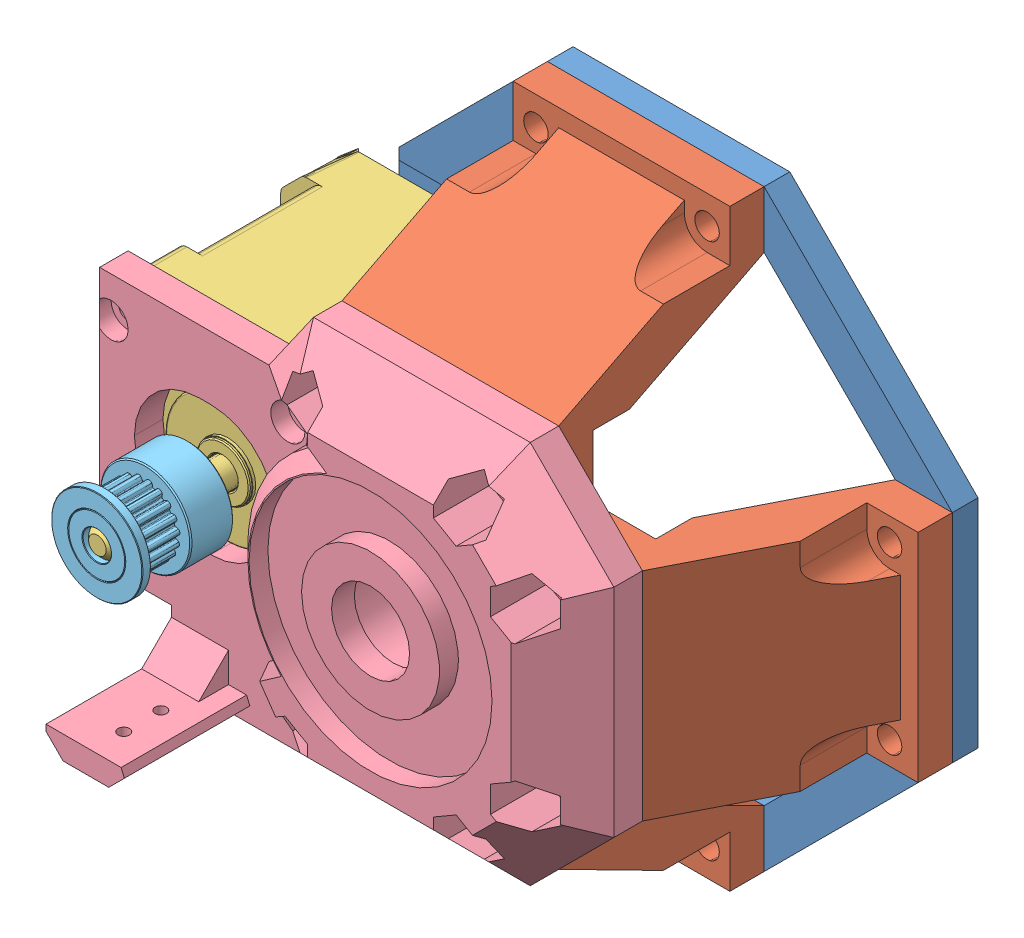
SolidWorks assembly 基座, configuration 默认. Lengths in mm.
7 component instances, 5 part files, 19 mates.
Components (placement in the parent):
- 基座底板-1: 基座底板 [默认] at origin size (101.5 104 4.5)
- 基座支架-1: 基座支架 [默认] at (148.9938 50.9835 0) x (0 -1 0) z (0 0 1) size (32 38 36)
- 基座支架-2: 基座支架 [默认] at origin size (32 38 36)
- 基座支架-3: 基座支架 [默认] at (50.9835 -148.9938 0) x (0 1 0) z (0 0 1) size (32 38 36)
- 基座电机-1: 基座电机 [默认] at (2.002 -0.002 0) size (51.25 48 66.15)
- 基座顶板-1: 基座顶板 [默认] at origin size (95.16 67.32 27)
- 基座小带轮-1: 基座小带轮 [默认] at (123.4059 0.6984 1.1039) x (-0.204066 -0.978957 0) z (0 0 1) size (16 16 16)
Mates (geometry in assembly coordinates):
- 重合1: coincident: plane of ? through (0 0 0) normal (0 0 1); plane of assembly through (0 0 0) normal (0 0 1)
- 重合2: coincident: plane of ? through (0 0 0) normal (0 1 0); plane of assembly through (0 0 0) normal (0 1 0)
- 重合3: coincident: plane of ? through (0 0 0) normal (1 0 0); plane of assembly through (0 0 0) normal (1 0 0)
- 重合4: coincident: plane of ? through (-96.0113 -266.0051 -63.2) normal (0 0 1); plane of 基座支架-1 through (80.9887 -93.5051 -63.2) normal (0 0 -1)
- 同心1: concentric: cylinder of ? through (84.9887 -96.0051 -63.2) axis (0 0 -1) radius 1.9; cylinder of 基座支架-1 through (84.9887 -96.0051 -34.2) axis (0 0 -1) radius 2.15
- 同心2: concentric: cylinder of ? through (114.9887 -96.0051 -63.2) axis (0 0 -1) radius 1.9; cylinder of 基座支架-1 through (114.9887 -96.0051 -34.2) axis (0 0 -1) radius 2.15
- 重合6: coincident: plane of ? through (-96.0113 -266.0051 -63.2) normal (0 0 1); plane of ? through (144.4887 -68.0051 -63.2) normal (0 0 -1)
- 同心3: concentric: cylinder of ? through (146.9887 -64.0051 -63.2) axis (0 0 -1) radius 1.9; cylinder of ? through (146.9887 -64.0051 -34.2) axis (0 0 -1) radius 2.15
- 同心4: concentric: cylinder of ? through (146.9887 -34.0051 -63.2) axis (0 0 -1) radius 1.9; cylinder of ? through (146.9887 -34.0051 -34.2) axis (0 0 -1) radius 2.15
- 重合7: coincident: plane of ? through (-96.0113 -266.0051 -63.2) normal (0 0 1); plane of 基座支架-3 through (118.9887 -4.5051 -63.2) normal (0 0 -1)
- 同心5: concentric: cylinder of ? through (84.9887 -2.0051 -63.2) axis (0 0 -1) radius 1.9; cylinder of 基座支架-3 through (84.9887 -2.0051 -34.2) axis (0 0 -1) radius 2.15
- 同心6: concentric: cylinder of ? through (114.9887 -2.0051 -63.2) axis (0 0 -1) radius 1.9; cylinder of 基座支架-3 through (114.9887 -2.0051 -34.2) axis (0 0 -1) radius 2.15
- 重合8: coincident: plane of ? through (-96.0113 -266.0051 -65.2) normal (0 0 1); plane of 基座电机-1 through (60.9887 -49.0051 -65.2) normal (0 0 -1)
- 重合9: coincident: plane of 基座支架-3 through (118.9887 -19.6751 -27.2) normal (0 0 1); plane of ? through (61.4887 68.4949 -27.2) normal (0 0 -1)
- 同心7: concentric: cylinder of 基座支架-1 through (114.9887 -74.0051 -13.2) axis (0 0 -1) radius 2.15; cylinder of ? through (114.9887 -74.0051 -21.2) axis (0 0 -1) radius 2.15
- 同心8: concentric: cylinder of 基座支架-1 through (84.9887 -74.0051 -13.2) axis (0 0 -1) radius 2.15; cylinder of ? through (84.9887 -74.0051 -21.2) axis (0 0 -1) radius 2.15
- 同心9: concentric: cylinder of 基座电机-1 through (62.9887 -49.0051 -24.7) axis (0 0 1) radius 2.5; cylinder of ? through (62.9887 -49.0051 -22.2) axis (0 0 -1) radius 11.4
- 平行1: parallel: plane of 基座电机-1 through (80.0637 -28.0051 -65.2) normal (0 1 0); plane of ? through (64.0887 -78.5651 -4.95) normal (0 1 0)
- 同心10: concentric: cylinder of assembly; cylinder of assembly; cylinder of 基座电机-1 through (62.9887 -49.0051 -24.7) axis (0 0 1) radius 2.5; cylinder of 基座小带轮-1 through (62.9887 -49.0051 -3.6961) axis (0 0 1) radius 2.5
